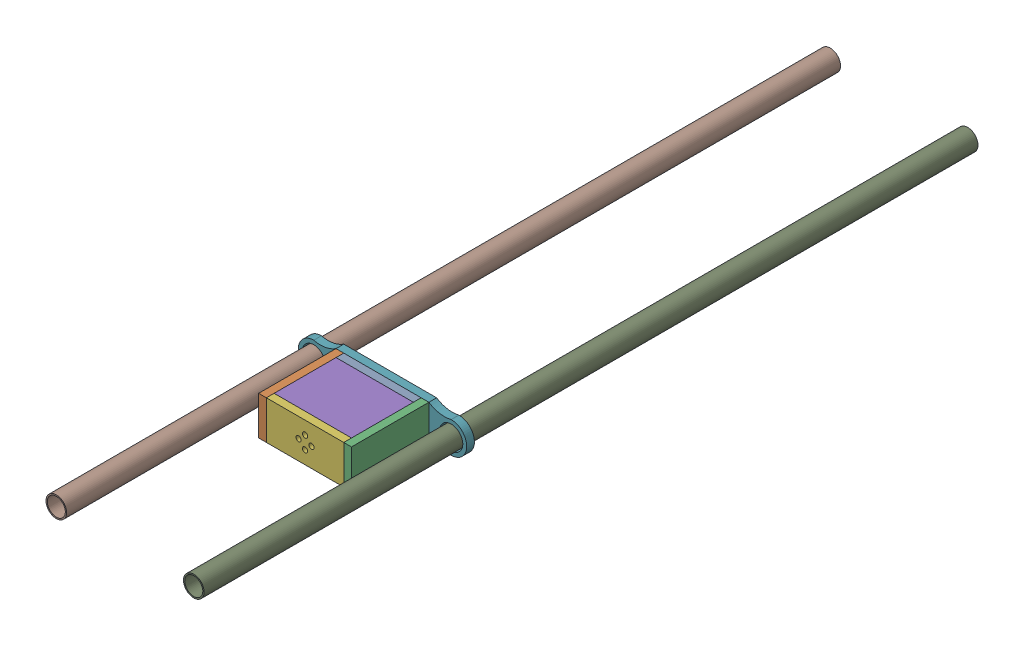
SolidWorks assembly counter weight, configuration Default. Lengths in mm.
Overall size (65.29 15 300).
9 component instances, 5 part files, 21 mates.
Components (placement in the parent):
- counter weight sides-1: counter weight sides [Default] at (-0.89 13.0886 6.8832) size (30 15 3)
- counter weight sides-3: counter weight sides [Default] at (-15.89 13.0886 21.8832) x (0 0 1) z (-1 0 0) size (30 15 3)
- counter weight sides-4: counter weight sides [Default] at (17.11 13.0886 21.8832) x (0 0 1) z (-1 0 0) size (30 15 3)
- Cw front and back-1: Cw front and back [Default] at (-0.89 8.5886 21.8832) x (0 0 1) z (0 -1 0) size (24 30 3)
- Cw front and back-2: Cw front and back [Default] at (-0.89 20.5886 21.8832) x (0 0 1) z (0 -1 0) size (24 30 3)
- counter weight top-1: counter weight top [Default] at (-0.89 13.0886 33.8832) size (30 15 3)
- counter weight base-1: counter weight base [Default] at (-0.89 13.0886 3.8832) size (65.29 15 3)
- spar-1: spar [Default] at (-27.5341 13.0886 -193.328) x (-0.030002 -0.99955 0) z (0 0 1) size (8 8 300)
- spar-2: spar [Default] at (25.754 13.0886 -193.328) x (0.995199 0.097873 0) z (0 0 1) size (8 8 300)
Mates (geometry in assembly coordinates):
- Coincident1: coincident anti-aligned: plane of counter weight sides-1 through (-15.89 5.5886 9.8832) normal (-1 0 0); plane of counter weight sides-3 through (-15.89 13.0886 21.8832) normal (1 0 0)
- Coincident2: coincident aligned: line of counter weight sides-1 through (-15.89 20.5886 6.8832) axis (0 -1 0); line of counter weight sides-3 through (-15.89 20.5886 6.8832) axis (0 -1 0)
- Coincident3: coincident aligned: plane of counter weight sides-1 through (-15.89 20.5886 9.8832) normal (0 1 0); plane of counter weight sides-3 through (-18.89 20.5886 6.8832) normal (0 1 0)
- Coincident13: coincident anti-aligned: plane of counter weight sides-3 through (-15.89 13.0886 21.8832) normal (1 0 0); plane of Cw front and back-1 through (-15.89 5.5886 9.8832) normal (-1 0 0)
- Coincident15: coincident anti-aligned: plane of counter weight sides-4 through (14.11 13.0886 21.8832) normal (-1 0 0); plane of Cw front and back-2 through (14.11 17.5886 9.8832) normal (1 0 0)
- Coincident17: coincident aligned: plane of counter weight sides-3 through (-18.89 5.5886 36.8832) normal (0 0 1); plane of counter weight top-1 through (-0.89 13.0886 36.8832) normal (0 0 1)
- Coincident18: coincident anti-aligned: line of Cw front and back-1 through (14.11 5.5886 33.8832) axis (-1 0 0); line of counter weight top-1 through (-15.89 5.5886 33.8832) axis (1 0 0)
- Coincident19: coincident anti-aligned: line of counter weight sides-3 through (-15.89 5.5886 36.8832) axis (0 1 0); line of counter weight top-1 through (-15.89 20.5886 36.8832) axis (0 -1 0)
- Parallel2: parallel aligned: plane of counter weight sides-3 through (-18.89 20.5886 6.8832) normal (0 1 0); plane of Cw front and back-2 through (-0.89 20.5886 21.8832) normal (0 1 0)
- Distance2: distance = 3 mm: plane of Cw front and back-2 through (14.11 17.5886 33.8832) normal (0 0 1); plane of counter weight sides-3 through (-18.89 5.5886 36.8832) normal (0 0 1)
- Coincident23: coincident aligned: plane of counter weight sides-3 through (-18.89 5.5886 6.8832) normal (0 -1 0); plane of Cw front and back-1 through (-0.89 5.5886 21.8832) normal (0 -1 0)
- Coincident25: coincident aligned: plane of counter weight sides-4 through (14.11 5.5886 6.8832) normal (0 -1 0); plane of Cw front and back-1 through (-0.89 5.5886 21.8832) normal (0 -1 0)
- Coincident26: coincident aligned: plane of counter weight sides-4 through (14.11 5.5886 36.8832) normal (0 0 1); plane of counter weight top-1 through (-0.89 13.0886 36.8832) normal (0 0 1)
- Coincident27: coincident aligned: plane of Cw front and back-1 through (-0.89 5.5886 21.8832) normal (0 -1 0); plane of counter weight top-1 through (-15.89 5.5886 36.8832) normal (0 -1 0)
- Coincident28: coincident aligned: line of counter weight sides-4 through (14.11 5.5886 36.8832) axis (0 1 0); line of counter weight top-1 through (14.11 5.5886 36.8832) axis (0 1 0)
- Distance4: distance = 0 mm: line of Cw front and back-2 through (-15.89 20.5886 9.8832) axis (1 0 0); line of counter weight sides-1 through (14.11 20.5886 9.8832) axis (-1 0 0)
- Coincident29: coincident aligned: line of counter weight sides-1 through (-15.89 5.5886 6.8832) axis (1 0 0); line of counter weight base-1 through (-18.89 5.5886 6.8832) axis (1 0 0)
- Coincident30: coincident: point of counter weight sides-3; moEndPointRef_w of counter weight base-1
- Concentric11: concentric aligned: cylinder of counter weight base-1 through (25.754 13.0886 6.8832) axis (0 0 -1) radius 6; cylinder of spar-2 through (25.754 13.0886 106.672) axis (0 0 -1) radius 4
- Concentric2: concentric aligned: cylinder of counter weight base-1 through (-27.5341 13.0886 6.8832) axis (0 0 -1) radius 4.5; cylinder of spar-1 through (-27.5341 13.0886 106.672) axis (0 0 -1) radius 4
- Coincident31: coincident aligned: plane of spar-1 through (-27.5341 13.0886 106.672) normal (0 0 1); plane of spar-2 through (25.754 13.0886 106.672) normal (0 0 1)
